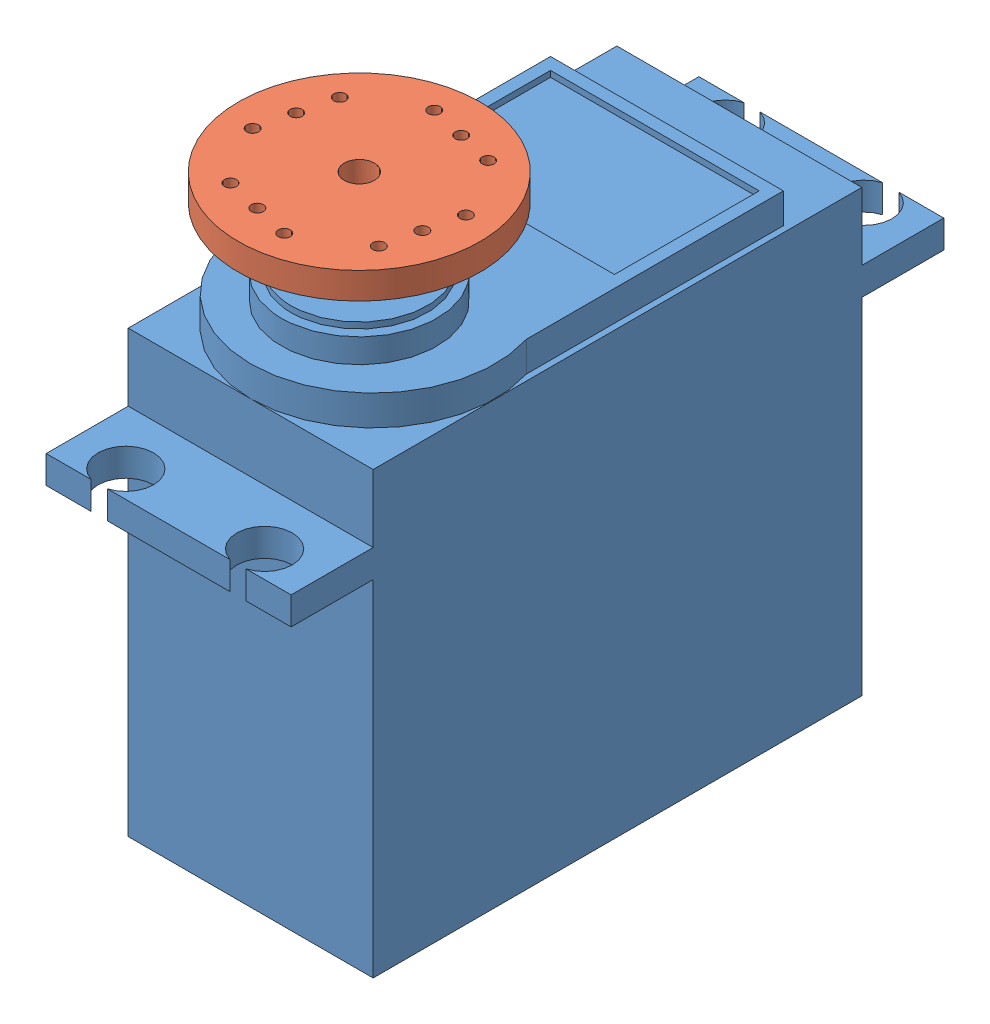
SolidWorks assembly 55gServoAndAttachment, configuration Default. Lengths in mm.
Overall size (24.11 48.3 54.1).
2 component instances, 2 part files, 2 mates.
Components (placement in the parent):
- 55gServoMotor-1: 55gServoMotor [Default] at (29.3026 10.0421 49.0781) size (20.3 45.5 54.1)
- CircularAttachment-1: CircularAttachment [Default] at (29.3026 56.1421 60.3281) x (0.973354 0 0.229307) z (-0.229307 0 0.973354) size (20.05 5.6 20.05)
Mates (geometry in assembly coordinates):
- Concentric1: concentric aligned: cylinder of 55gServoMotor-1 through (29.3026 55.5421 60.3281) axis (0 -1 0) radius 3; cylinder of ServoAttachment-1 through (29.3026 55.5421 60.3281) axis (0 -1 0) radius 3
- Coincident1: coincident anti-aligned: plane of 55gServoMotor-1 through (29.3026 55.5421 60.3281) normal (0 1 0); plane of ServoAttachment-1 through (29.3026 55.5421 60.3281) normal (0 -1 0)
